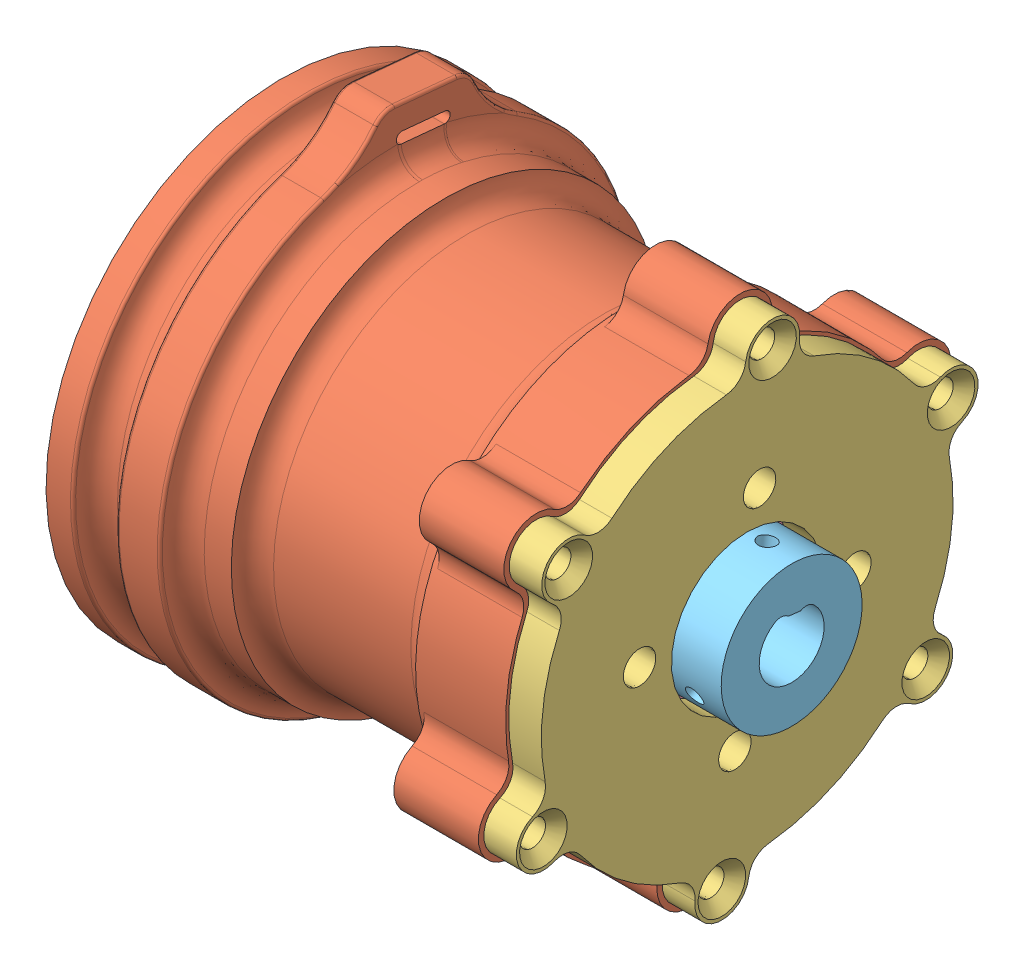
SolidWorks assembly planet-GB-4to1, configuration Default. Lengths in mm.
Overall size (47 53.01 48.84).
8 component instances, 5 part files, 16 mates.
Components (placement in the parent):
- RingGearN30-1: RingGearN30 [Default] at origin size (5 35 35)
- transmission-planetshell-4march2013-abs-print-1: transmission-planetshell-4march2013-abs-print [Default] x (1 0 0) z (0 0.114178 0.99346) size (39.9 48.35 43.6)
- LidPlanetGB-1: LidPlanetGB [Default] at (7 0 0) x (1 0 0) z (0 0.114178 0.99346) size (3 46 40.51)
- Planet_Revolving_FollowerN10h3mm-1: Planet_Revolving_FollowerN10h3mm [Planet_Revolving_Follower01] at (3.85 9.9346 -1.1418) x (0 0 1) z (-1 0 0) size (12 12 2.5)
- Sun_DriverN10h4mm-1: Sun_DriverN10h4mm [Sun_Driver01] at (4.6 0 0) x (0 0.113007 0.993594) z (-1 0 0) size (13 13 10)
- Planet_Revolving_FollowerN10h3mm-2: Planet_Revolving_FollowerN10h3mm [Planet_Revolving_Follower01] at (3.85 -1.1418 -9.9346) x (0 -0.072859 0.997342) z (-1 0 0) size (12 12 2.5)
- Planet_Revolving_FollowerN10h3mm-3: Planet_Revolving_FollowerN10h3mm [Planet_Revolving_Follower01] at (3.85 -9.9346 1.1418) x (0 0 1) z (-1 0 0) size (12 12 2.5)
- Planet_Revolving_FollowerN10h3mm-4: Planet_Revolving_FollowerN10h3mm [Planet_Revolving_Follower01] at (3.85 1.1418 9.9346) x (0 0 1) z (-1 0 0) size (12 12 2.5)
Mates (geometry in assembly coordinates):
- Concentric45: concentric anti-aligned: cylinder of RingGearN30-1 through (0 0 0) axis (-1 0 0) radius 17.5; cylinder of transmission-planetshell-4march2013-abs-print-1 through (0 0 0) axis (1 0 0) radius 19.3
- Concentric46: concentric aligned: cylinder of transmission-planetshell-4march2013-abs-print-1 through (0 0 0) axis (1 0 0) radius 19.3; cylinder of LidPlanetGB-1 through (7 0 0) axis (1 0 0) radius 7
- Coincident49: coincident anti-aligned: plane of transmission-planetshell-4march2013-abs-print-1 through (5.5 17.3856 -1.9981) normal (1 0 0); plane of LidPlanetGB-1 through (5.5 6.9542 -0.7992) normal (-1 0 0)
- Concentric51: concentric aligned: cylinder of transmission-planetshell-4march2013-abs-print-1 through (5.5 20.3659 -2.3407) axis (1 0 0) radius 0.8; cylinder of LidPlanetGB-1 through (8.5 20.3659 -2.3407) axis (1 0 0) radius 1.2
- Parallel1: parallel anti-aligned: plane of RingGearN30-1 through (2.5 17 0) normal (1 0 0); plane of Planet_Revolving_FollowerN10h3mm-1 through (2.6 9.9346 -1.1418) normal (-1 0 0)
- Distance1: distance = 0.1 mm anti-aligned: plane of RingGearN30-1 through (2.5 17 0) normal (1 0 0); plane of Planet_Revolving_FollowerN10h3mm-1 through (2.6 9.9346 -1.1418) normal (-1 0 0)
- Concentric52: concentric anti-aligned: cylinder of LidPlanetGB-1 through (8.5 9.9346 -1.1418) axis (1 0 0) radius 1.5; cylinder of Planet_Revolving_FollowerN10h3mm-1 through (3.85 9.9346 -1.1418) axis (-1 0 0) radius 1.5
- Distance2: distance = 0.1 mm anti-aligned: plane of RingGearN30-1 through (2.5 17 0) normal (1 0 0); plane of Planet_Revolving_FollowerN10h3mm-2 through (2.6 -1.1418 -9.9346) normal (-1 0 0)
- Concentric53: concentric anti-aligned: cylinder of LidPlanetGB-1 through (8.5 -1.1418 -9.9346) axis (1 0 0) radius 1.5; cylinder of Planet_Revolving_FollowerN10h3mm-2 through (3.85 -1.1418 -9.9346) axis (-1 0 0) radius 1.5
- Concentric54: concentric anti-aligned: cylinder of LidPlanetGB-1 through (7 0 0) axis (1 0 0) radius 7; cylinder of Sun_DriverN10h4mm-1 through (12.6 0 0) axis (-1 0 0) radius 6.5
- Coincident50: coincident anti-aligned: plane of RingGearN30-1 through (0 7 0) normal (-1 0 0); plane of transmission-planetshell-4march2013-abs-print-1 through (0 15.8954 -1.8268) normal (1 0 0)
- Coaxiale1: concentric anti-aligned: cylinder of LidPlanetGB-1 through (8.5 1.1418 9.9346) axis (1 0 0) radius 1.5; cylinder of Planet_Revolving_FollowerN10h3mm-4 through (3.85 1.1418 9.9346) axis (-1 0 0) radius 1.5
- Coaxiale3: concentric anti-aligned: cylinder of LidPlanetGB-1 through (8.5 -9.9346 1.1418) axis (1 0 0) radius 1.5; cylinder of Planet_Revolving_FollowerN10h3mm-3 through (3.85 -9.9346 1.1418) axis (-1 0 0) radius 1.5
- Coïncidente1: coincident aligned: plane of Planet_Revolving_FollowerN10h3mm-1 through (2.6 9.9346 -1.1418) normal (-1 0 0); plane of Planet_Revolving_FollowerN10h3mm-4 through (2.6 1.1418 9.9346) normal (-1 0 0)
- Coïncidente2: coincident aligned: plane of Planet_Revolving_FollowerN10h3mm-3 through (2.6 -9.9346 1.1418) normal (-1 0 0); plane of Planet_Revolving_FollowerN10h3mm-4 through (2.6 1.1418 9.9346) normal (-1 0 0)
- Distance3: distance = 4.1 mm aligned: plane of LidPlanetGB-1 through (8.5 6.9542 -0.7992) normal (1 0 0); plane of Sun_DriverN10h4mm-1 through (12.6 0 0) normal (1 0 0)
